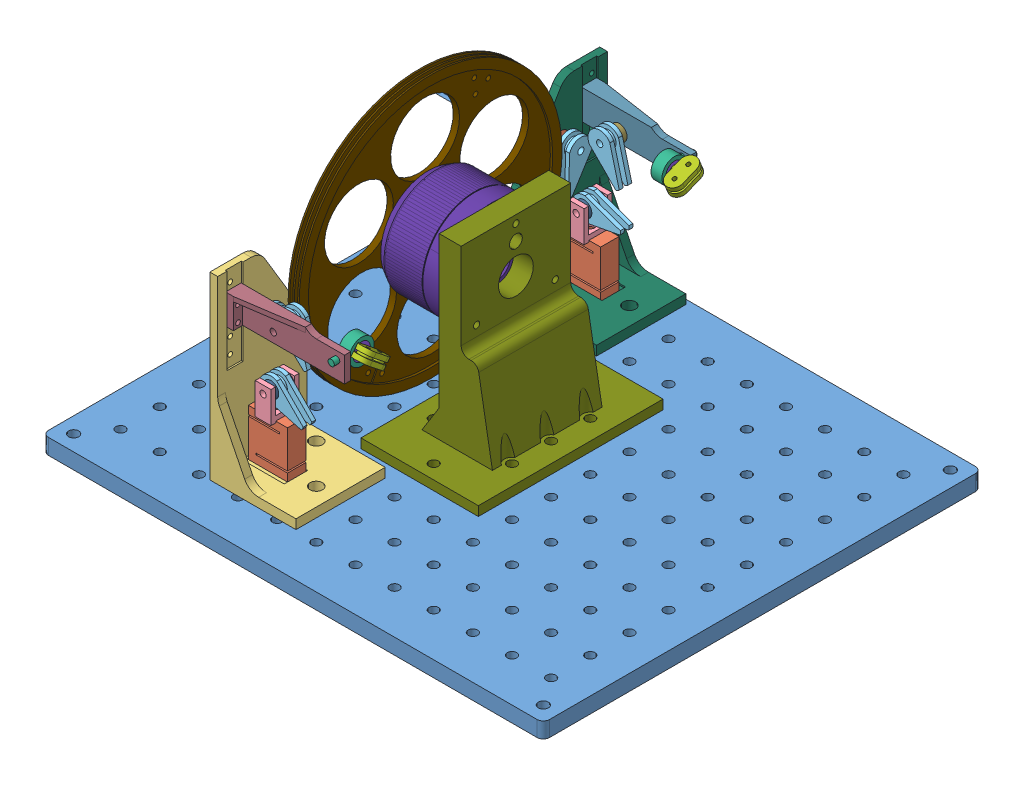
SolidWorks assembly 板套装竖 _右, configuration 默认. Lengths in mm.
Overall size (406.25 226.8 312.04).
40 component instances, 19 part files, 8 mates.
Components (placement in the parent):
- 定位板-1: 定位板 [默认] at (18.8982 -8.715 320) size (320 10 280)
- 拉力组件-1: 拉力组件 [默认] at (8.7723 4.2671 464.3646) x (-0.51712 0 0.855913) z (-0.855913 0 -0.51712) size (77.23 115 96.55)
  - 拉力计-1: 拉力计 [Default] at (-10.0735 32.0178 81.8814) x (-0.51712 0 -0.855913) z (0 1 0) size (25 11.8 30)
  - 六角柱与拉力机连接板-1: 六角柱与拉力机连接板 [默认] at (-35.6476 -2.9822 75.134) x (0.855913 0 -0.51712) z (0.51712 0 0.855913) size (57 115 55)
  - 拉力连接件-1: 拉力连接件 [默认] at (-21.5874 31.0178 74.2335) x (0.51712 0 0.855913) z (-0.855913 0 0.51712) size (10 20 18)
  - NT002滑轮-1: NT002滑轮 [默认] at (-22.5057 78.0178 82.3825) x (0.645954 -0.656075 -0.390268) z (0.561544 0.754695 -0.33927) size (15 8 35.78)
  - NT002滑轮-2: NT002滑轮 [默认] at (-22.8713 46.0178 75.0092) x (0.259381 -0.865107 0.429315) z (0.447364 0.501588 0.740456) size (15 8 35.78)
  - 万向绳-1: 万向绳 [默认] at (-30.8183 -5.1943 51.2199) x (0 -1 0) z (0.855913 0 -0.51712) size (16 18.5 26.19) (flexible)
    - 万向绳2-1: 万向绳2 [默认] at (-97.2122 22.5289 -4) size (16 7 24)
    - 万向绳1-1: 万向绳1 [默认] at (-97.4442 35.2789 1.8956) x (0.624404 0 -0.781101) z (0 1 0) size (20 7 13.5)
    - 万向绳3-1: 万向绳3 [默认] at (-97.2122 27.0289 -4) size (11 2.5 11)
    - 万向绳4-1: 万向绳4 [默认] at (-97.2122 27.0289 -4) x (-0.837169 0 -0.546944) z (-0.546944 0 0.837169) size (8 5 8)
  - NT002滑轮-3: NT002滑轮 [默认] at (-28.0425 87.0178 66.45) x (0.441055 -0.522062 0.730015) z (0.269968 0.852908 0.44684) size (15 8 35.78)
  - 拉力计滑轮垫片-1: 拉力计滑轮垫片 [默认] at (-25.0111 46.0178 76.302) x (0.267413 0.855913 0.44261) z (0.44261 -0.51712 0.732587) size (10 2 10)
  - 滑轮1垫片-1: 滑轮1垫片 [默认] at (-21.2129 78.0178 84.5223) x (0.732587 -0.51712 -0.44261) z (-0.44261 -0.855913 0.267413) size (10 4.5 10)
  - 滑轮2垫片-1: 滑轮2垫片 [默认] at (-23.335 87.0178 63.6059) x (0.267413 -0.855913 0.44261) z (0.44261 0.51712 0.732587) size (10 4.5 10)
  - 拉力计滑轮垫片-2: 拉力计滑轮垫片 [默认] at (-16.452 46.0178 71.1308) x (0.267413 0.855913 0.44261) z (0.44261 -0.51712 0.732587) size (10 2 10)
  - 滑轮2连接板2.0-2: 滑轮2连接板2.0 [默认] at (-0.8225 87.0178 78.6289) x (0 -1 0) z (0.855913 0 -0.51712) size (19 70 10)
- 拉力组件右-1: 拉力组件右 [默认] at (15.2111 2.0613 277.7031) x (-0.51712 0 0.855913) z (-0.855913 0 -0.51712) size (81.92 115 89.71)
  - 拉力计-1: 拉力计 [Default] at (-18.1606 34.2237 94.2901) x (-0.51712 0 -0.855913) z (0 1 0) size (25 11.8 30)
  - 拉力连接件-1: 拉力连接件 [默认] at (-29.6744 33.2237 86.6422) x (0.51712 0 0.855913) z (-0.855913 0 0.51712) size (10 20 18)
  - NT002滑轮-1: NT002滑轮 [默认] at (-22.0336 80.2237 89.62) x (0.817883 0.294773 -0.494143) z (-0.2523 0.955567 0.152433) size (15 8 35.78)
  - NT002滑轮-2: NT002滑轮 [默认] at (-30.9583 48.2237 87.4178) x (0.040785 -0.996885 0.067506) z (0.515509 0.07887 0.853247) size (15 8 35.78)
  - 万向绳-1: 万向绳 [默认] at (-45.5814 191.4358 67.6621) x (0 1 0) z (-0.855913 0 0.51712) size (16 18.5 26.19) (flexible)
    - 万向绳2-1: 万向绳2 [默认] at (-97.2122 22.5289 -4) size (16 7 24)
    - 万向绳1-1: 万向绳1 [默认] at (-92.1831 35.2789 -0.9144) x (-0.375978 0 -0.926629) z (0 1 0) size (20 7 13.5)
    - 万向绳3-1: 万向绳3 [默认] at (-97.2122 27.0289 -4) size (11 2.5 11)
    - 万向绳4-1: 万向绳4 [默认] at (-97.2122 27.0289 -4) x (-0.837169 0 -0.546944) z (-0.546944 0 0.837169) size (8 5 8)
  - NT002滑轮-3: NT002滑轮 [默认] at (-33.5618 89.2237 77.3074) x (-0.449174 0.495502 -0.743452) z (0.256234 0.868607 0.424106) size (15 8 35.78)
  - 拉力计滑轮垫片-1: 拉力计滑轮垫片 [默认] at (-33.0981 48.2237 88.7106) x (0.267413 0.855913 0.44261) z (0.44261 -0.51712 0.732587) size (10 2 10)
  - 滑轮1垫片-1: 滑轮1垫片 [默认] at (-20.7408 80.2237 91.7598) x (0.732587 -0.51712 -0.44261) z (-0.44261 -0.855913 0.267413) size (10 4.5 10)
  - 滑轮2连接板2.0右-1: 滑轮2连接板2.0右 [默认] at (-35.4429 89.2237 107.0683) x (0 1 0) z (-0.855913 0 0.51712) size (19 70 10)
  - 滑轮2垫片-1: 滑轮2垫片 [默认] at (-38.2693 89.2237 80.1515) x (0.267413 0.855913 0.44261) z (0.44261 -0.51712 0.732587) size (10 4.5 10)
  - 拉力计滑轮垫片-2: 拉力计滑轮垫片 [默认] at (-24.539 48.2237 83.5394) x (0.267413 0.855913 0.44261) z (0.44261 -0.51712 0.732587) size (10 2 10)
  - 六角柱与拉力机连接板右-2: 六角柱与拉力机连接板右 [默认] at (-43.7346 -0.7763 87.5427) x (0.855913 0 -0.51712) z (0.51712 0 0.855913) size (57 115 55)
- 电机固定组件-1: 电机固定组件 [默认] at (-5.1614 70.5052 457.5) x (-1 0 0) z (0 0 -1) size (111 226.8 226.8)
  - 电机固定1.0-1: 电机固定1.0 [默认] at (-49.0596 -69.2202 115) size (75 137.5 118)
  - RoboMaster GM6020 直流无刷电机-1: RoboMaster GM6020 直流无刷电机 [默认] at (116.9883 16.7798 150) x (0 0.866025 0.5) z (1 0 0) size (66.7 66.7 45)
  - 轮组2.0-1: 轮组2.0 [默认] at (40.4404 16.7798 150) x (0 -0.885679 -0.464298) z (0 -0.464298 0.885679) size (168 7.5 168)
  - 绳调节1.0-1: 绳调节1.0 [默认] at (45.9404 71.6919 178.7865) x (0 0.885679 0.464298) z (0 0.464298 -0.885679) size (18 16 20)
Mates (geometry in assembly coordinates):
- 重合1: coincident: plane of 定位板-1 through (18.8982 1.285 320) normal (0 1 0); plane of 拉力组件-1/六角柱与拉力机连接板-1 through (-37.1018 1.285 420) normal (0 -1 0)
- 重合2: coincident: plane of 定位板-1 through (18.8982 1.285 320) normal (0 1 0); plane of 拉力组件右-1/六角柱与拉力机连接板右-2 through (-37.1018 1.285 195) normal (0 -1 0)
- 同心1: concentric: circle of 定位板-1; circle of 拉力组件右-1/六角柱与拉力机连接板右-2
- 同心2: concentric aligned: circle of 定位板-1; circle of 拉力组件右-1/六角柱与拉力机连接板右-2
- 同心4: concentric: circle of 定位板-1; circle of 电机固定组件-1/电机固定1.0-1
- 同心3: concentric aligned: circle of 定位板-1; circle of 拉力组件-1/六角柱与拉力机连接板-1
- 同心5: concentric: cylinder of 定位板-1 through (31.3982 -8.715 307.5) axis (0 1 0) radius 3; circle of 电机固定组件-1/电机固定1.0-1
- 重合5: coincident anti-aligned: plane of 定位板-1 through (18.8982 1.285 320) normal (0 1 0); plane of 电机固定组件-1/电机固定1.0-1 through (43.8982 1.285 342.5) normal (0 -1 0)
